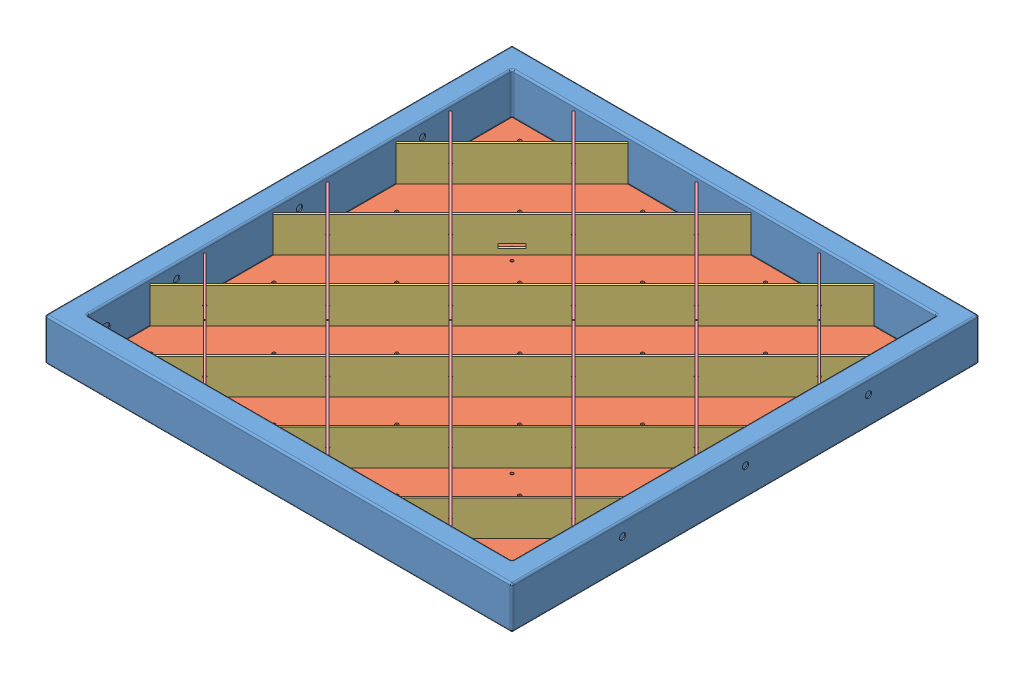
SolidWorks assembly SPR-V1 2000.00-A Pressing plate upper assembly, configuration Default. Lengths in mm.
Overall size (1330 123 1330).
4 component instances, 4 part files, 10 mates.
Components (placement in the parent):
- SPR-V1 2100.01-A Pressing plate frame upper-1: SPR-V1 2100.01-A Pressing plate frame upper [Default] at origin size (1330 120 1330)
- SPR-V1 2100.02-A Heating plate upper-1: SPR-V1 2100.02-A Heating plate upper [Default] x (-1 0 0) z (0 -1 0) size (1200 1200 10)
- SPR-V1 2100.03-A Support structure upper B-1: SPR-V1 2100.03-A Support structure upper B [Default] at (0 107 0) x (-1 0 0) z (0 0 1) size (1210 100 1210)
- SPR-V1 2100.03-A Pressing plate support structure upper A-2: SPR-V1 2100.03-A Pressing plate support structure upper A [Default] at (0 7 0) size (1210 100 1210)
Mates (geometry in assembly coordinates):
- InPlace1: in place: plane of SPR-V1 2100.01-A Pressing plate frame upper-1 through (0 0 0) normal (0 -1 0); plane of SPR-V1 2100.02-A Heating plate upper-1 through (0 0 0) normal (0 -1 0); moOrthogonalPlaneRef_w of SPR-V1 2100.01-A Pressing plate frame upper-1 through (0 0 0) normal (0 -1 0); plane of SPR-V1 2100.02-A Heating plate upper-1 through (0 0 0) normal (0 0 -1); plane of SPR-V1 2100.01-A Pressing plate frame upper-1 through (0 0 0) normal (0 -1 0); plane of SPR-V1 2100.02-A Heating plate upper-1 through (0 0 0) normal (-1 0 0); plane of SPR-V1 2100.01-A Pressing plate frame upper-1 through (0 0 0) normal (0 -1 0); unknown of SPR-V1 2100.02-A Heating plate upper-1
- Coincident1: coincident: plane of SPR-V1 2100.01-A Pressing plate frame upper-1; plane of SPR-V1 2100.02-A Heating plate upper-1
- Coincident2: coincident: moOrthogonalPlaneRef_w of SPR-V1 2100.01-A Pressing plate frame upper-1 through (0 0 0) normal (0 0 -1); plane of SPR-V1 2100.02-A Heating plate upper-1 through (0 0 0) normal (0 0 -1)
- Coincident3: coincident: moOrthogonalPlaneRef_w of SPR-V1 2100.01-A Pressing plate frame upper-1 through (0 0 0) normal (1 0 0); plane of SPR-V1 2100.02-A Heating plate upper-1 through (0 0 0) normal (-1 0 0)
- Coincident1: coincident: plane of SPR-V1 2100.02-A Heating plate upper-1 through (0 7 0) normal (0 1 0); plane of SPR-V1 2100.03-A Support structure upper B-1 through (0 7 0) normal (0 -1 0)
- Coincident2: coincident: plane of SPR-V1 2100.03-A Support structure upper B-1 through (0 107 0) normal (0 0 1); plane of assembly through (0 0 0) normal (0 0 1)
- Coincident3: coincident: plane of SPR-V1 2100.03-A Support structure upper B-1 through (0 107 0) normal (-1 0 0); plane of assembly through (0 0 0) normal (1 0 0)
- Coincident4: coincident: plane of SPR-V1 2100.03-A Pressing plate support structure upper A-2 through (0 7 0) normal (0 0 1); plane of assembly through (0 0 0) normal (0 0 1)
- Coincident5: coincident: plane of SPR-V1 2100.03-A Pressing plate support structure upper A-2 through (0 7 0) normal (1 0 0); plane of assembly through (0 0 0) normal (1 0 0)
- Coincident6: coincident: plane of SPR-V1 2100.03-A Support structure upper B-1 through (0 107 0) normal (0 1 0); plane of SPR-V1 2100.03-A Pressing plate support structure upper A-2 through (0 107 0) normal (0 1 0)
